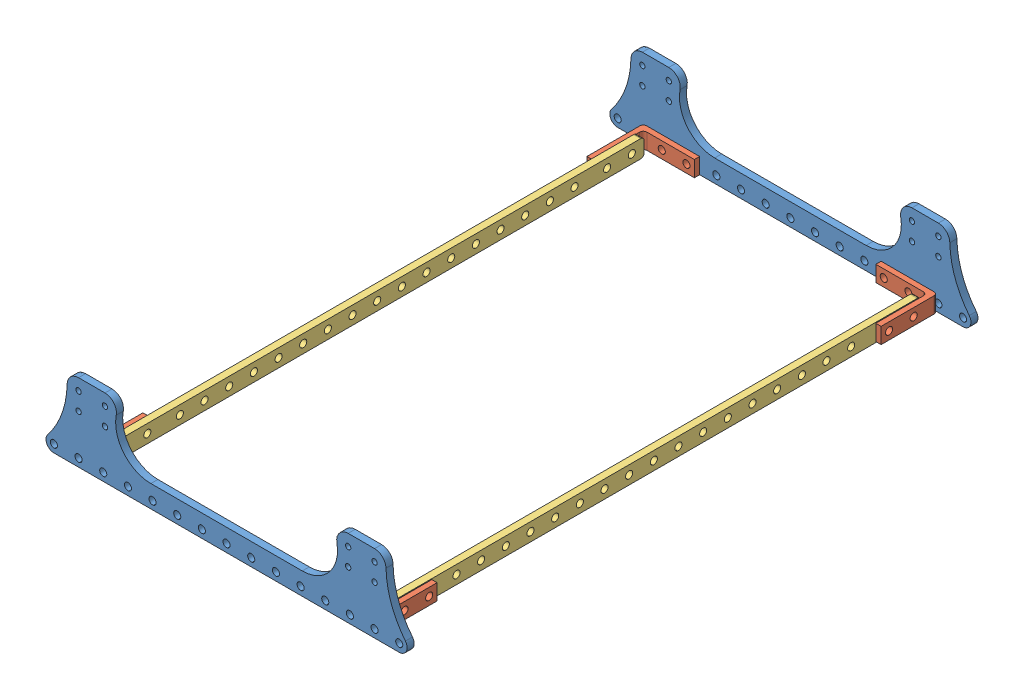
SolidWorks assembly 防卡2, configuration 默认. Lengths in mm.
Overall size (207 46 324).
8 component instances, 3 part files, 12 mates.
Components (placement in the parent):
- 纵板-1: 纵板 [默认] at origin size (207 46 4)
- 角件-1: 角件 [默认] at (-83.5 -28 0) x (1 0 0) z (0 1 0) size (32 32 9)
- 横挡板-1: 横挡板 [默认] at (-80.5 -28 -158) x (0 0 -1) z (1 0 0) size (303 10 4)
- 角件-2: 角件 [默认] at (-83.5 -28 -316) x (0 0 1) z (0 1 0) size (32 32 9)
- 角件-3: 角件 [默认] at (83.5 -28 0) x (-1 0 0) z (0 -1 0) size (32 32 9)
- 横挡板-2: 横挡板 [默认] at (76.5 -28 -158) x (0 0 -1) z (1 0 0) size (303 10 4)
- 角件-4: 角件 [默认] at (83.5 -28 -316) x (0 0 1) z (0 -1 0) size (32 32 9)
- 纵板-2: 纵板 [默认] at (0 0 -320) size (207 46 4)
Mates (geometry in assembly coordinates):
- 重合1: coincident anti-aligned: plane of 纵板-1 through (0 0 0) normal (0 0 -1); plane of 角件-1 through (-83.5 -23.5 0) normal (0 0 1)
- 同心1: concentric aligned: cylinder of 纵板-1 through (-70 -28 4) axis (0 0 -1) radius 2.025; circle of 角件-1
- 同心2: concentric anti-aligned: cylinder of 纵板-1 through (-56 -28 4) axis (0 0 -1) radius 2.025; cylinder of 角件-1 through (-56 -28 -9) axis (0 0 1) radius 2.025
- 重合2: coincident anti-aligned: plane of 角件-1 through (-80.5 -23.5 0) normal (1 0 0); plane of 横挡板-1 through (-80.5 -28 -158) normal (-1 0 0)
- 同心3: concentric aligned: cylinder of 角件-1 through (-74.5 -28 -27.5) axis (-1 0 0) radius 2.025; cylinder of 横挡板-1 through (-76.5 -28 -27.5) axis (-1 0 0) radius 2.025
- 同心4: concentric aligned: cylinder of 角件-1 through (-74.5 -28 -13.5) axis (-1 0 0) radius 2.025; cylinder of 横挡板-1 through (-76.5 -28 -13.5) axis (-1 0 0) radius 2.025
- 重合3: coincident anti-aligned: plane of 横挡板-1 through (-80.5 -28 -158) normal (-1 0 0); plane of 角件-2 through (-80.5 -23.5 -316) normal (1 0 0)
- 同心5: concentric aligned: cylinder of 横挡板-1 through (-76.5 -28 -302.5) axis (-1 0 0) radius 2.025; cylinder of 角件-2 through (-74.5 -28 -302.5) axis (-1 0 0) radius 2.025
- 同心6: concentric aligned: cylinder of 横挡板-1 through (-76.5 -28 -288.5) axis (-1 0 0) radius 2.025; cylinder of 角件-2 through (-74.5 -28 -288.5) axis (-1 0 0) radius 2.025
- 重合4: coincident anti-aligned: plane of 角件-4 through (83.5 -32.5 -316) normal (0 0 -1); plane of 纵板-2 through (0 0 -316) normal (0 0 1)
- 同心7: concentric aligned: cylinder of 角件-4 through (70 -28 -307) axis (0 0 -1) radius 2.025; cylinder of 纵板-2 through (70 -28 -316) axis (0 0 -1) radius 2.025
- 同心8: concentric aligned: cylinder of 角件-4 through (56 -28 -307) axis (0 0 -1) radius 2.025; cylinder of 纵板-2 through (56 -28 -316) axis (0 0 -1) radius 2.025
